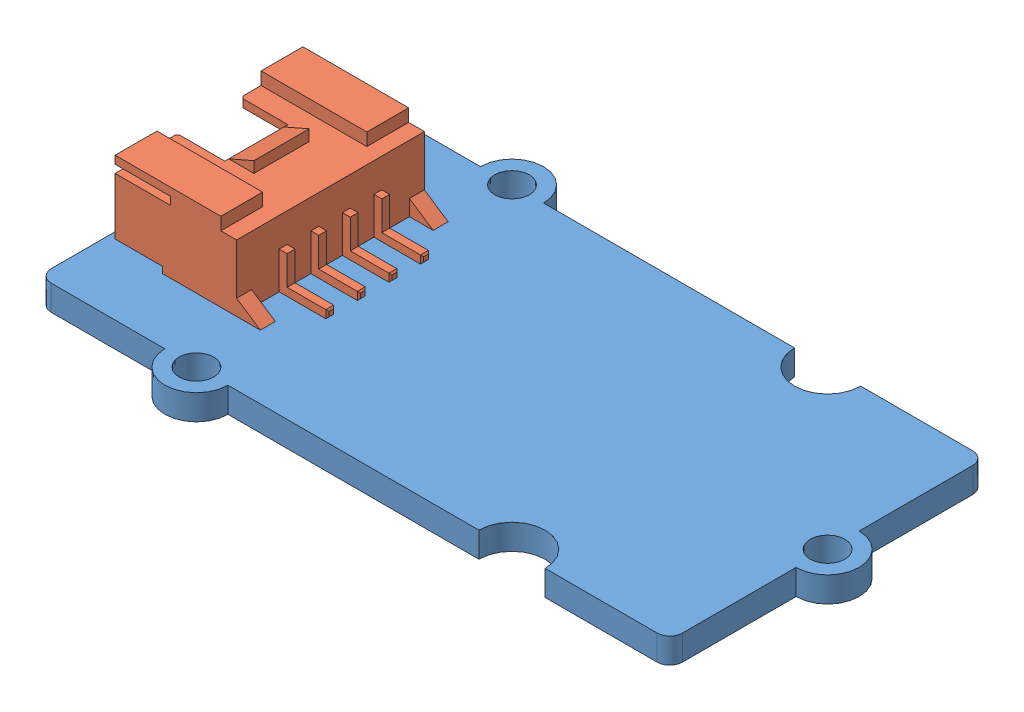
SolidWorks assembly PCB Grove 20x40 SMD Horizontal - Red LED Button v1.0, configuration Défaut. Lengths in mm.
Overall size (42 6.6 24).
2 component instances, 2 part files, 3 mates.
Components (placement in the parent):
- PCB Grove 20x40 - Red LED Button-1: PCB Grove 20x40 - Red LED Button [Défaut] at (-8.4131 3.685 42) size (42 1.6 24)
- Connector Grove SMD Horizontal-1: Connector Grove SMD Horizontal [Défaut] at (-19.9131 9.485 42) x (0 0 -1) z (0 1 0) size (12.95 10.75 5)
Mates (geometry in assembly coordinates):
- Coïncidente1: coincident anti-aligned: plane of PCB Grove 20x40 - Red Led Button-1 through (-8.4131 3.685 42) normal (0 0 1); plane of Connector Grove SMD Horizontal-1 through (-19.9131 9.485 42) normal (0 0 -1)
- Coïncidente2: coincident anti-aligned: plane of PCB Grove 20x40 - Red Led Button-1 through (-8.4131 4.485 42) normal (0 1 0); plane of Connector Grove SMD Horizontal-1 through (-27.6131 4.485 47) normal (0 -1 0)
- Distance1: distance = 0.8 mm aligned: plane of Connector Grove SMD Horizontal-1 through (-27.6131 9.485 42) normal (-1 0 0); plane of PCB Grove 20x40 - Red Led Button-1 through (-28.4131 4.485 42) normal (-1 0 0)
